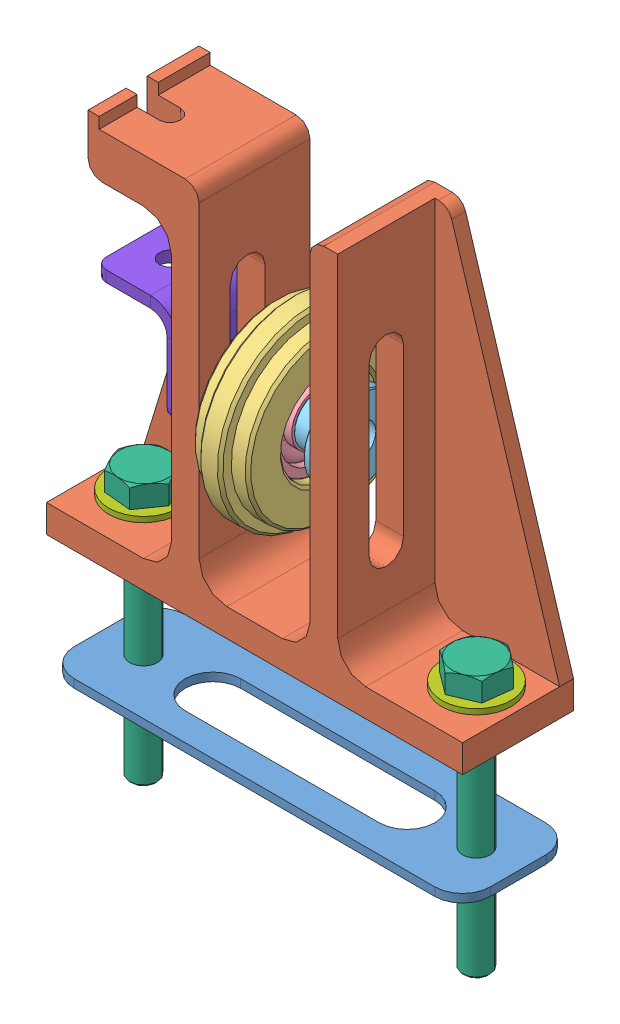
SolidWorks assembly Chain Tensioner_Idea 2, configuration Default. Lengths in mm.
Overall size (95.25 138.46 46.65).
12 component instances, 8 part files, 23 mates.
Components (placement in the parent):
- Chain Tensioner Flange_Bottom-1: Chain Tensioner Flange_Bottom [Default] at (-85.4348 -32.6429 34.9749) x (1 0 0) z (0 1 0) size (95.25 25.4 1.91)
- Chain Tensioner Flange_Idea 2-1: Chain Tensioner Flange_Idea 2 [Default] at (-85.4348 -5.3379 34.9749) size (95.25 88.9 25.4)
- Wheel-1: Wheel [Default] at (-85.3788 37.7738 36.5624) x (0 0.083839 -0.996479) z (-1 0 0) size (43.18 43.18 12.7)
- instrument ball bearing_68_am-1: instrument ball bearing_68_am [AFBMA 12.1.4.1 - 0080-22 - Full,SI,NC,Full_68] at (-85.4348 37.7738 36.5624) size (7 22 22)
- Spacer_Chain Tensioner-1: Spacer_Chain Tensioner [Default] at (-93.5348 37.7738 36.5624) x (0 -0.023853 -0.999715) z (-1 0 0) size (19.05 19.05 9.2)
- Spacer_Chain Tensioner-2: Spacer_Chain Tensioner [Default] at (-77.3348 37.7738 36.5624) x (0 0.969135 0.246529) z (1 0 0) size (19.05 19.05 9.2)
- hex bolt_ai-2: hex bolt_ai [HBOLT 0.2500-28x2.25x0.75-N] at (-123.5348 7.0319 34.9749) x (0 -1 0) z (0.093352 0 -0.995633) size (61.93 12.85 11.13)
- hex bolt_ai-3: hex bolt_ai [HBOLT 0.2500-28x2.25x0.75-N] at (-47.3348 7.0319 34.9749) x (0 -1 0) z (-0.992674 0 -0.120823) size (61.93 12.85 11.13)
- flat washer type a selected narrow_ai-3: flat washer type a selected narrow_ai [Selected Narrow FW 0.266] at (-123.5348 1.0121 34.9749) x (0 -1 0) z (0 0 1) size (1.24 15.88 15.88)
- flat washer type a selected narrow_ai-4: flat washer type a selected narrow_ai [Selected Narrow FW 0.266] at (-47.3348 1.0121 34.9749) x (0 -1 0) z (0 0 1) size (1.24 15.88 15.88)
- flat washer type a selected narrow_ai-5: flat washer type a selected narrow_ai [Selected Narrow FW 0.438] at (-104.4848 56.2571 36.5624) size (2.11 22.23 22.23) (hidden)
- Chain Tensioner Bracket-1: Chain Tensioner Bracket [Default] at (-123.5348 52.3788 36.5624) size (19.05 22.86 19.05)
Mates (geometry in assembly coordinates):
- Distance1: distance = 25.4 mm anti-aligned: plane of Chain Tensioner Flange_Bottom-1 through (-37.8098 -30.7379 47.6749) normal (0 1 0); plane of Chain Tensioner Flange_Idea 2-1 through (-133.0598 -5.3379 47.6749) normal (0 -1 0)
- Coincident2: coincident aligned: plane of Chain Tensioner Flange_Bottom-1 through (-133.0598 -30.7379 47.6749) normal (0 0 1); plane of Chain Tensioner Flange_Idea 2-1 through (-133.0598 -5.3379 47.6749) normal (0 0 1)
- Coincident3: coincident aligned: plane of Chain Tensioner Flange_Bottom-1 through (-133.0598 -30.7379 22.2749) normal (-1 0 0); plane of Chain Tensioner Flange_Idea 2-1 through (-133.0598 1.0121 47.6749) normal (-1 0 0)
- Coincident4: coincident anti-aligned: plane of Wheel-1 through (-88.9348 37.7738 36.5624) normal (1 0 0); plane of instrument ball bearing_68_am-1 through (-88.9348 43.8738 36.5624) normal (-1 0 0)
- Concentric1: concentric aligned: cylinder of Wheel-1 through (-91.7288 37.7738 36.5624) axis (1 0 0) radius 10.9873; cylinder of instrument ball bearing_68_am-1 through (-106.0723 37.7738 36.5624) axis (1 0 0) radius 11
- Coincident5: coincident anti-aligned: plane of instrument ball bearing_68_am-1 through (-88.9348 43.8738 36.5624) normal (-1 0 0); plane of Spacer_Chain Tensioner-1 through (-88.9348 37.7738 36.5624) normal (1 0 0)
- Coincident6: coincident anti-aligned: plane of Chain Tensioner Flange_Idea 2-1 through (-98.1348 83.5621 47.6749) normal (1 0 0); plane of Spacer_Chain Tensioner-1 through (-98.1348 37.7738 36.5624) normal (-1 0 0)
- Coincident7: coincident anti-aligned: plane of Spacer_Chain Tensioner-2 through (-72.7348 37.7738 36.5624) normal (1 0 0); plane of Chain Tensioner Flange_Idea 2-1 through (-72.7348 1.0121 47.6749) normal (-1 0 0)
- Concentric9: concentric anti-aligned: cylinder of Chain Tensioner Flange_Bottom-1 through (-123.5348 -30.7379 34.9749) axis (0 -1 0) radius 3.175; cylinder of hex bolt_ai-2 through (-123.5348 7.0319 34.9749) axis (0 1 0) radius 3.175
- Concentric10: concentric anti-aligned: cylinder of Chain Tensioner Flange_Bottom-1 through (-47.3348 -30.7379 34.9749) axis (0 -1 0) radius 3.175; cylinder of hex bolt_ai-3 through (-47.3348 7.0319 34.9749) axis (0 1 0) radius 3.175
- Concentric11: concentric aligned: cylinder of hex bolt_ai-2 through (-123.5348 7.0319 34.9749) axis (0 1 0) radius 3.175; cylinder of flat washer type a selected narrow_ai-3 through (-123.5348 35.9371 34.9749) axis (0 1 0) radius 3.3782
- Concentric12: concentric aligned: cylinder of hex bolt_ai-3 through (-47.3348 7.0319 34.9749) axis (0 1 0) radius 3.175; cylinder of flat washer type a selected narrow_ai-4 through (-47.3348 35.9371 34.9749) axis (0 1 0) radius 3.3782
- Coincident8: coincident anti-aligned: plane of Chain Tensioner Flange_Idea 2-1 through (-104.4848 83.5621 47.6749) normal (-1 0 0); plane of flat washer type a selected narrow_ai-5 through (-104.4848 61.8197 36.5624) normal (1 0 0)
- Coincident10: coincident anti-aligned: plane of hex bolt_ai-2 through (-129.9299 2.2567 34.3753) normal (0 -1 0); plane of flat washer type a selected narrow_ai-3 through (-115.5973 2.2567 34.9749) normal (0 1 0)
- Coincident11: coincident anti-aligned: plane of Chain Tensioner Flange_Idea 2-1 through (-104.4848 1.0121 47.6749) normal (0 1 0); plane of flat washer type a selected narrow_ai-3 through (-120.1566 1.0121 34.9749) normal (0 -1 0)
- Coincident12: coincident anti-aligned: plane of hex bolt_ai-3 through (-48.1109 2.2567 41.3509) normal (0 -1 0); plane of flat washer type a selected narrow_ai-4 through (-39.3973 2.2567 34.9749) normal (0 1 0)
- Coincident13: coincident anti-aligned: plane of Chain Tensioner Flange_Idea 2-1 through (-66.3848 1.0121 47.6749) normal (0 1 0); plane of flat washer type a selected narrow_ai-4 through (-43.9566 1.0121 34.9749) normal (0 -1 0)
- Concentric13: concentric anti-aligned: cylinder of Spacer_Chain Tensioner-1 through (-98.1348 37.7738 36.5624) axis (1 0 0) radius 3.9688; cylinder of Spacer_Chain Tensioner-2 through (-72.7348 37.7738 36.5624) axis (-1 0 0) radius 3.9688
- Concentric14: concentric aligned: cylinder of Spacer_Chain Tensioner-1 through (-98.1348 37.7738 36.5624) axis (1 0 0) radius 3.9688; cylinder of Chain Tensioner Bracket-1 through (-104.4848 37.7738 36.5624) axis (1 0 0) radius 3.9688
- Concentric15: concentric aligned: cylinder of instrument ball bearing_68_am-1 through (-106.0723 37.7738 36.5624) axis (1 0 0) radius 4; cylinder of Chain Tensioner Bracket-1 through (-104.4848 37.7738 36.5624) axis (1 0 0) radius 3.9688
- Tangent1: tangent anti-aligned: plane of Chain Tensioner Flange_Idea 2-1 through (-133.0598 58.1621 32.5936) normal (0 0 1); cylinder of Chain Tensioner Bracket-1 through (-104.4848 37.7738 36.5624) axis (1 0 0) radius 3.9688
- Coincident14: coincident anti-aligned: plane of Chain Tensioner Flange_Idea 2-1 through (-104.4848 83.5621 47.6749) normal (-1 0 0); plane of Chain Tensioner Bracket-1 through (-104.4848 46.0288 46.0874) normal (1 0 0)
- Parallel1: parallel anti-aligned: plane of Chain Tensioner Flange_Idea 2-1 through (-85.4348 39.1121 25.4499) normal (0 0 1); plane of Chain Tensioner Bracket-1 through (-104.4848 46.0288 27.0374) normal (0 0 -1)
